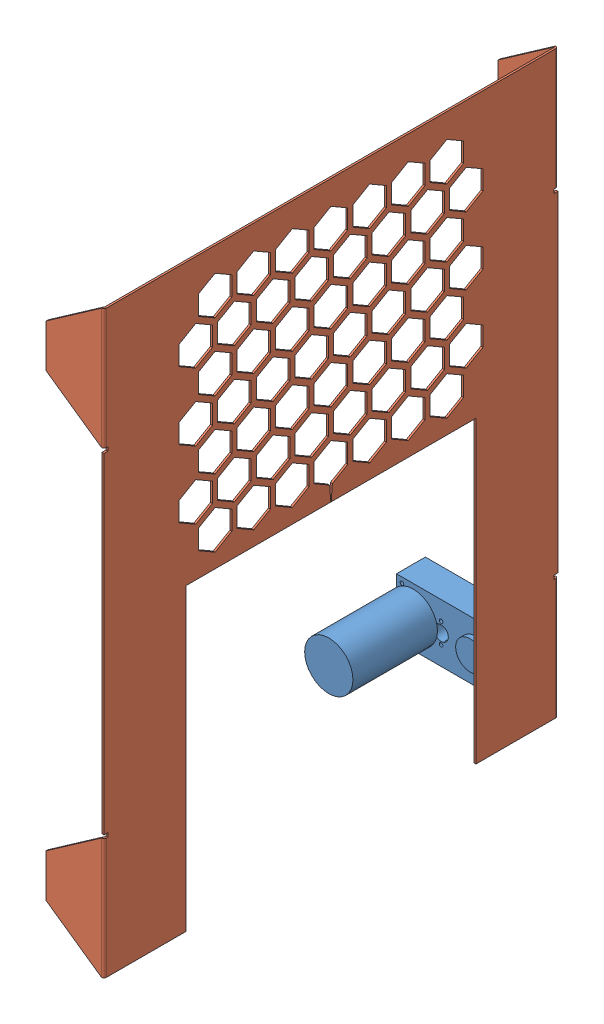
SolidWorks assembly Assem1, configuration Default. Lengths in mm.
Overall size (162.55 762 613.7).
2 component instances, 2 part files, 0 mates.
Components (placement in the parent):
- Pretty Damn Close Mechanum Geabox Stand-In-1: Pretty Damn Close Mechanum Geabox Stand-In [Default] at (20.6011 87.3519 116.9994) size (149.22 76.2 187.33)
- Base Plate-1: Base Plate [Default] at (103.7729 428.6396 375.0968) x (0 1 0) z (0 0 1) size (762 76.2 596.9)
